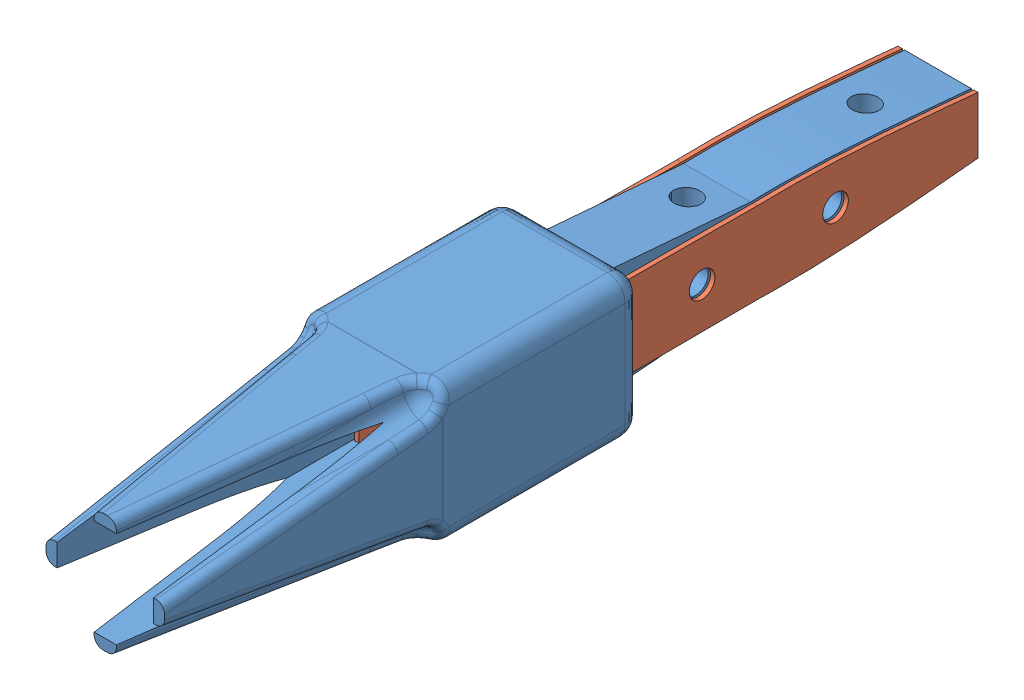
SolidWorks assembly TailSurfaceConnection, configuration Default. Lengths in mm.
Overall size (45.64 40.39 237.69).
3 component instances, 2 part files, 4 mates.
Components (placement in the parent):
- Tail Attachment-1: Tail Attachment [Default] at (86.8607 135.4515 175.6815) size (45.64 40.39 228.22)
- Tail Attachment CF slide-1: Tail Attachment CF slide [Default] at (76.7007 132.4161 132.917) x (0 0 1) z (-1 0 0) size (155.14 23.62 1.27)
- Tail Attachment CF slide-2: Tail Attachment CF slide [Default] at (98.2907 132.4161 132.917) x (0 0 1) z (-1 0 0) size (155.14 23.62 1.27)
Mates (geometry in assembly coordinates):
- Distance3: distance = 0.635 mm anti-aligned: plane of Tail Attachment-1 through (96.3857 122.8785 64.9883) normal (1 0 0); plane of Tail Attachment CF slide-2 through (97.0207 132.4161 132.917) normal (-1 0 0)
- Coincident2: coincident: line of Tail Attachment-1 through (77.3357 127.3211 64.9883) axis (1 0 0); line of Tail Attachment CF slide-2 through (97.0207 127.3211 64.9883) axis (1 0 0)
- Distance1: distance = 0.635 mm anti-aligned: plane of Tail Attachment-1 through (77.3357 122.8785 64.9883) normal (-1 0 0); plane of Tail Attachment CF slide-1 through (76.7007 132.4161 132.917) normal (1 0 0)
- Coincident4: coincident: line of Tail Attachment-1 through (77.3357 143.5819 64.9883) axis (1 0 0); line of Tail Attachment CF slide-1 through (75.4307 143.5819 64.9883) axis (1 0 0)
